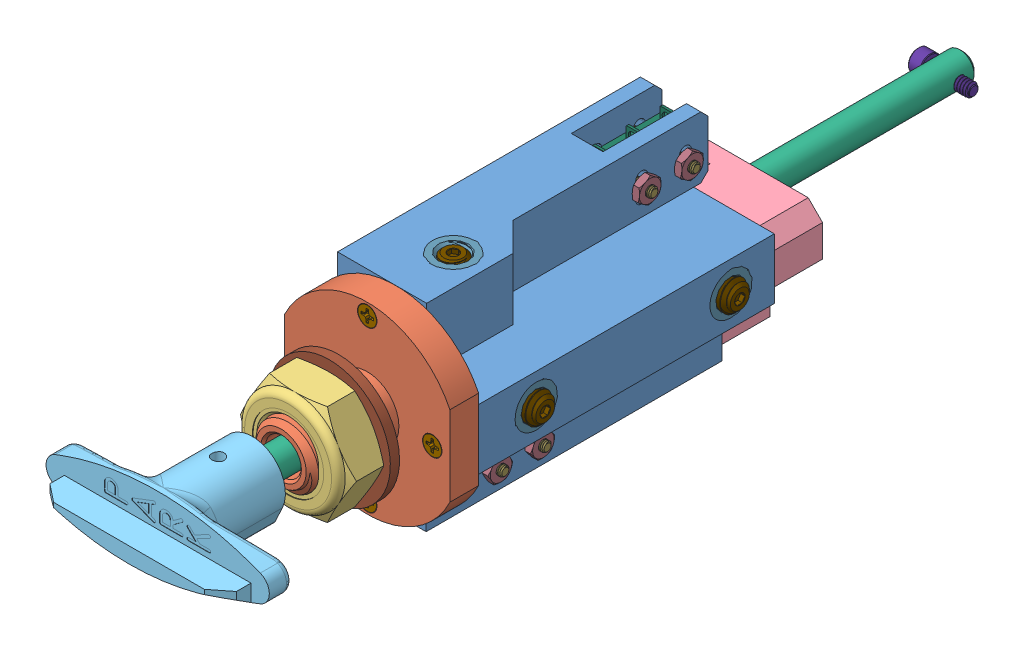
SolidWorks assembly Parking Brake Handle Mechanism, configuration Stowed. Lengths in mm.
Overall size (49.4 44.55 184.53).
50 component instances, 18 part files, 78 mates.
Components (placement in the parent):
- Parking Brake Mechanism Body-1: Parking Brake Mechanism Body [Default] at (0 0 49.2125) x (-1 0 0) z (0 0 -1) size (39.75 43.81 68.58)
- Wing Fold Mechanism Upper Cap-1: Wing Fold Mechanism Upper Cap [Default] at (0 0 -19.177) size (36.58 40.64 28.08)
- Wing Fold Handle Retaining Nut-1: Wing Fold Handle Retaining Nut [Default] at (0 0 -17.145) size (25.66 23.83 11.45)
- Parking Brake Mechanism End Cap-1: Parking Brake Mechanism End Cap [Default] at (0 0 -29.0195) x (-1 0 0) z (0 0 -1) size (39.75 30.18 10.67)
- Parking Brake Handle-1: Parking Brake Handle [Default] at (0 0 6.0325) x (0 1 0) z (0 0 1) size (15.42 49.4 27.31)
- Parking Brake Mechanism Shaft-3: Parking Brake Mechanism Shaft [Default] at (0 0 -46.0375) x (0 -1 0) z (0 0 1) size (6.35 6.35 176.28)
- 6338K411-1: 6338K411 [Default] at (0 0 36.3855) x (1 0 0) z (0 -1 0) size (12.7 6.35 12.7)
- 6338K411-2: 6338K411 [Default] at (0 0 -39.6875) x (-0.923728 -0.383049 0) z (-0.383049 0.923728 0) size (12.7 6.35 12.7)
- 93365A112-14: 93365A112 [Default] at (0 -11.1125 42.7355) x (1 0 0) z (0 -1 0) size (3.58 4.78 3.58)
- 93365A112-15: 93365A112 [Default] at (0 17.68 36.3855) x (1 0 0) z (0 -1 0) size (3.58 4.78 3.58)
- 93365A112-16: 93365A112 [Default] at (14.378 0 36.3855) x (1 0 0) z (0 -1 0) size (3.58 4.78 3.58)
- 93365A112-17: 93365A112 [Default] at (0 -17.68 36.3855) x (1 0 0) z (0 -1 0) size (3.58 4.78 3.58)
- 93365A112-18: 93365A112 [Default] at (-14.378 0 36.3855) x (1 0 0) z (0 -1 0) size (3.58 4.78 3.58)
- 93365A112-12: 93365A112 [Default] at (12.3825 0 -29.0195) x (-0.923728 -0.383049 0) z (0.383049 -0.923728 0) size (3.58 4.78 3.58)
- 93365A112-13: 93365A112 [Default] at (-15.8591 0 -29.0195) x (-0.85131 -0.524663 0) z (0.524663 -0.85131 0) size (3.58 4.78 3.58)
- 93365A112-19: 93365A112 [Default] at (0 -18.2626 -29.0195) x (-0.85131 -0.524663 0) z (0.524663 -0.85131 0) size (3.58 4.78 3.58)
- 96640A027-9: 96640A027 [Default] at (-14.378 0 41.4401) size (4.11 4.11 12.73)
- 96640A027-10: 96640A027 [Default] at (0 -17.68 41.4401) size (4.11 4.11 12.73)
- 96640A027-11: 96640A027 [Default] at (0 17.68 41.4401) size (4.11 4.11 12.73)
- 96640A027-12: 96640A027 [Default] at (14.378 0 41.4401) size (4.11 4.11 12.73)
- 96640A025-1: 96640A025 [Default] at (0 -11.1125 47.7901) size (4.11 4.11 9.56)
- 96640A027-5: 96640A027 [Default] at (12.3825 0 -35.6489) x (0.628171 -0.778076 0) z (0 0 -1) size (4.11 4.11 12.73)
- 96640A027-6: 96640A027 [Default] at (-15.8591 0 -35.6489) x (0.743591 -0.668635 0) z (0 0 -1) size (4.11 4.11 12.73)
- 96640A027-8: 96640A027 [Default] at (0 -6.0071 75.7643) x (-0.410756 0 -0.911745) z (0 -1 0) size (4.11 4.11 12.73)
- 96640A027-13: 96640A027 [Default] at (0 -18.2626 -35.6489) x (0.995409 0.095714 0) z (0 0 -1) size (4.11 4.11 12.73)
- 92141A034-1: 92141A034 [Default] at (0 0 49.0855) x (1 0 0) z (0 -1 0) size (26.97 2.03 26.97)
- 91249A060 - PHS, 2-56 X .625, 18-8, BLACK OXIDE-10: 91249A060 - PHS, 2-56 X .625, 18-8, BLACK OXIDE [91249A060] at (9.1948 -18.2683 21.3928) x (0 0 -1) z (-1 0 0) size (4.24 4.24 17.48)
- 91249A060 - PHS, 2-56 X .625, 18-8, BLACK OXIDE-9: 91249A060 - PHS, 2-56 X .625, 18-8, BLACK OXIDE [91249A060] at (9.1948 -18.2683 12.0329) x (0 0.158553 -0.987351) z (-1 0 0) size (4.24 4.24 17.48)
- 91249A060 - PHS, 2-56 X .625, 18-8, BLACK OXIDE-13: 91249A060 - PHS, 2-56 X .625, 18-8, BLACK OXIDE [91249A060] at (-18.2683 9.1948 21.3928) x (-0.143817 0 0.989604) z (0 -1 0) size (4.24 4.24 17.48)
- 91249A060 - PHS, 2-56 X .625, 18-8, BLACK OXIDE-8: 91249A060 - PHS, 2-56 X .625, 18-8, BLACK OXIDE [91249A060] at (-18.2683 9.1948 12.0329) x (-0.33861 0 0.940927) z (0 -1 0) size (4.24 4.24 17.48)
- 91249A060 - PHS, 2-56 X .625, 18-8, BLACK OXIDE-14: 91249A060 - PHS, 2-56 X .625, 18-8, BLACK OXIDE [91249A060] at (2.9527 12.3755 -27.1886) x (0 0.421154 -0.906989) z (-1 0 0) size (4.24 4.24 17.48)
- 91249A060 - PHS, 2-56 X .625, 18-8, BLACK OXIDE-12: 91249A060 - PHS, 2-56 X .625, 18-8, BLACK OXIDE [91249A060] at (2.9527 12.3748 -17.8127) x (0 0.429957 -0.902849) z (-1 0 0) size (4.24 4.24 17.48)
- 91841A003-5: 91841A003 [Default] at (7.474 -18.2683 21.3928) x (0 -1 0) z (0 0 1) size (4.76 1.72 5.5)
- 91841A003-7: 91841A003 [Default] at (7.474 -18.2683 12.0329) x (0 -0.987351 -0.158553) z (0 -0.158553 0.987351) size (4.76 1.72 5.5)
- 91841A003-9: 91841A003 [Default] at (-18.2683 7.474 21.3928) x (-0.989604 0 -0.143817) z (0.143817 0 -0.989604) size (4.76 1.72 5.5)
- 91841A003-11: 91841A003 [Default] at (-18.2683 7.474 12.0329) x (-0.940927 0 -0.33861) z (0.33861 0 -0.940927) size (4.76 1.72 5.5)
- 91841A003-13: 91841A003 [Default] at (1.2319 12.3755 -27.1886) x (0 -0.906989 -0.421154) z (0 -0.421154 0.906989) size (4.76 1.72 5.5)
- 91841A003-15: 91841A003 [Default] at (1.2319 12.3755 -17.8287) x (0 -0.902849 -0.429957) z (0 -0.429957 0.902849) size (4.76 1.72 5.5)
- 93365A160 - INSERT, .25-20, BRASS, FOR PLASTICS-1: 93365A160 - INSERT, .25-20, BRASS, FOR PLASTICS [93365A160] at (18.288 0 -19.3675) x (0 0.381849 -0.924225) z (0 -0.924225 -0.381849) size (9.53 8.41 9.53)
- 93365A160 - INSERT, .25-20, BRASS, FOR PLASTICS-2: 93365A160 - INSERT, .25-20, BRASS, FOR PLASTICS [93365A160] at (18.288 0 23.6855) x (0 0.523557 -0.85199) z (0 -0.85199 -0.523557) size (9.53 8.41 9.53)
- 93365A160 - INSERT, .25-20, BRASS, FOR PLASTICS-4: 93365A160 - INSERT, .25-20, BRASS, FOR PLASTICS [93365A160] at (0 20.32 23.6855) x (-0.834128 0 -0.551571) z (0.551571 0 -0.834128) size (9.53 8.41 9.53)
- 7658K15-1: 7658K15 [Clipped] at (0 -20.6305 16.6049) x (0 0 1) z (-1 0 0) size (19.99 17.27 6.5)
- 7658K15-2: 7658K15 [Clipped] at (-6.242 14.7377 -22.4007) x (0 0 -1) z (-1 0 0) size (19.99 17.27 6.5)
- 7658K15-3: 7658K15 [Clipped] at (-20.6305 0 16.6049) x (0 0 1) z (0 1 0) size (19.99 17.27 6.5)
- 90176A102 - SPACER, UNTHREADED, .125 X #8 X .250, NYLON 6, BLACK-1: 90176A102 - SPACER, UNTHREADED, .125 X #8 X .250, NYLON 6, BLACK [94639A201] at (-4.7625 0 -25.7175) x (0 0.978585 -0.205844) z (1 0 0) size (6.35 6.35 3.17)
- 91251A108 - SHCS, 4-40 x .375, STEEL, BLACK-OXIDE-1: 91251A108 - SHCS, 4-40 x .375, STEEL, BLACK-OXIDE [91251A108] at (3.175 0 -25.7175) x (0 -0.927315 -0.374281) z (1 0 0) size (4.65 4.65 12.74)
- 91251A108 - SHCS, 4-40 x .375, STEEL, BLACK-OXIDE-2: 91251A108 - SHCS, 4-40 x .375, STEEL, BLACK-OXIDE [91251A108] at (6.35 0 -85.0646) x (0 -0.898283 -0.439417) z (1 0 0) size (4.65 4.65 12.74)
- 5901A142 - SPRING PLUNGER, .25-20 X .625 BODY, .125 X .035 NOSE, 3-7LBS FORCE, STEEL, BLACK-1: 5901A142 - SPRING PLUNGER, .25-20 X .625 BODY, .125 X .035 NOSE, 3-7LBS FORCE, STEEL, BLACK [5901A142] at (0 11.7475 23.6855) x (1 0 0) z (0 0 -1) size (6.42 18.35 6.4)
- 5901A142 - SPRING PLUNGER, .25-20 X .625 BODY, .125 X .035 NOSE, 3-7LBS FORCE, STEEL, BLACK-2: 5901A142 - SPRING PLUNGER, .25-20 X .625 BODY, .125 X .035 NOSE, 3-7LBS FORCE, STEEL, BLACK [5901A142] at (11.7475 0 23.6855) x (0 -1 0) z (0 0 -1) size (6.42 18.35 6.4)
- 5901A142 - SPRING PLUNGER, .25-20 X .625 BODY, .125 X .035 NOSE, 3-7LBS FORCE, STEEL, BLACK-3: 5901A142 - SPRING PLUNGER, .25-20 X .625 BODY, .125 X .035 NOSE, 3-7LBS FORCE, STEEL, BLACK [5901A142] at (11.7475 0 -19.3675) x (0 -1 0) z (0 0 -1) size (6.42 18.35 6.4)
Mates (geometry in assembly coordinates):
- Concentric43: concentric anti-aligned: cylinder of Parking Brake Mechanism Shaft-3 through (0 0 87.1855) axis (0 0 -1) radius 3.175; cylinder of Parking Brake Handle-1 through (0 0 68.1355) axis (0 0 1) radius 3.2385
- Concentric44: concentric aligned: cylinder of Parking Brake Mechanism Shaft-3 through (0 -3.175 75.7643) axis (0 -1 0) radius 0.889; cylinder of Parking Brake Handle-1 through (0 -7.3025 75.7643) axis (0 -1 0) radius 1.3526
- Concentric45: concentric anti-aligned: cylinder of Parking Brake Mechanism Shaft-3 through (-3.175 0 -25.7175) axis (-1 0 0) radius 1.1303; cylinder of 91251A108 - SHCS, 4-40 x .375, STEEL, BLACK-OXIDE-1 through (-9.1948 0 -25.7175) axis (1 0 0) radius 2.3241
- Tangent1: tangent aligned: cylinder of Parking Brake Mechanism Shaft-3 through (0 0 87.1855) axis (0 0 -1) radius 3.175; plane of 91251A108 - SHCS, 4-40 x .375, STEEL, BLACK-OXIDE-1 through (3.175 0 -25.7175) normal (1 0 0)
- Coincident71: coincident anti-aligned: plane of 7658K15-1 through (0 -20.6305 16.6049) normal (-1 0 0); plane of assembly through (0 0 0) normal (1 0 0)
- Distance2: distance = 20.6305 mm aligned: plane of 7658K15-1 through (0 -20.6305 16.6049) normal (0 1 0); plane of assembly through (0 0 0) normal (0 1 0)
- Coincident83: coincident aligned: plane of 7658K15-3 through (-20.6305 0 16.6049) normal (0 1 0); plane of assembly through (0 0 0) normal (0 1 0)
- Coincident84: coincident: plane of 7658K15-1 through (-3.2512 -11.3595 6.61) normal (0 0 -1); plane of 7658K15-3 through (-11.3595 3.2512 6.61) normal (0 0 -1)
- Distance6: distance = 20.6305 mm aligned: plane of 7658K15-3 through (-20.6305 0 16.6049) normal (1 0 0); plane of assembly through (0 0 0) normal (1 0 0)
- Coincident86: coincident aligned: plane of 5901A142 - SPRING PLUNGER, .25-20 X .625 BODY, .125 X .035 NOSE, 3-7LBS FORCE, STEEL, BLACK-1 through (0 11.7475 23.6855) normal (1 0 0); plane of assembly through (0 0 0) normal (1 0 0)
- Tangent3: tangent anti-aligned: cylinder of Parking Brake Mechanism Shaft-3 through (0 0 87.1855) axis (0 0 -1) radius 3.175; plane of 5901A142 - SPRING PLUNGER, .25-20 X .625 BODY, .125 X .035 NOSE, 3-7LBS FORCE, STEEL, BLACK-1 through (0 3.175 23.6855) normal (0 -1 0)
- Concentric47: concentric anti-aligned: cylinder of 91251A108 - SHCS, 4-40 x .375, STEEL, BLACK-OXIDE-1 through (-9.1948 0 -25.7175) axis (1 0 0) radius 2.3241; cylinder of 90176A102 - SPACER, UNTHREADED, .125 X #8 X .250, NYLON 6, BLACK-1 through (-3.175 0 -25.7175) axis (-1 0 0) radius 1.4605
- Coincident87: coincident anti-aligned: plane of 91251A108 - SHCS, 4-40 x .375, STEEL, BLACK-OXIDE-1 through (-6.35 0 -25.7175) normal (1 0 0); plane of 90176A102 - SPACER, UNTHREADED, .125 X #8 X .250, NYLON 6, BLACK-1 through (-6.35 0 -25.7175) normal (-1 0 0)
- Coincident88: coincident aligned: plane of 5901A142 - SPRING PLUNGER, .25-20 X .625 BODY, .125 X .035 NOSE, 3-7LBS FORCE, STEEL, BLACK-1 through (0 11.7475 23.6855) normal (0 0 -1); plane of 5901A142 - SPRING PLUNGER, .25-20 X .625 BODY, .125 X .035 NOSE, 3-7LBS FORCE, STEEL, BLACK-2 through (11.7475 0 23.6855) normal (0 0 -1)
- Coincident89: coincident anti-aligned: plane of 5901A142 - SPRING PLUNGER, .25-20 X .625 BODY, .125 X .035 NOSE, 3-7LBS FORCE, STEEL, BLACK-2 through (11.7475 0 23.6855) normal (0 -1 0); plane of assembly through (0 0 0) normal (0 1 0)
- Tangent4: tangent anti-aligned: cylinder of Parking Brake Mechanism Shaft-3 through (0 0 87.1855) axis (0 0 -1) radius 3.175; plane of 5901A142 - SPRING PLUNGER, .25-20 X .625 BODY, .125 X .035 NOSE, 3-7LBS FORCE, STEEL, BLACK-2 through (3.175 0 23.6855) normal (-1 0 0)
- Coincident91: coincident: plane of Parking Brake Mechanism Body-1 through (-9.4615 3.302 49.2125) normal (0 -1 0); line of 7658K15-2 through (-7.3469 3.302 -20.3306) axis (1 0 0)
- Coincident92: coincident aligned: plane of 5901A142 - SPRING PLUNGER, .25-20 X .625 BODY, .125 X .035 NOSE, 3-7LBS FORCE, STEEL, BLACK-2 through (11.7475 0 23.6855) normal (-1 0 0); plane of 5901A142 - SPRING PLUNGER, .25-20 X .625 BODY, .125 X .035 NOSE, 3-7LBS FORCE, STEEL, BLACK-3 through (11.7475 0 -19.3675) normal (-1 0 0)
- Coincident93: coincident aligned: plane of 5901A142 - SPRING PLUNGER, .25-20 X .625 BODY, .125 X .035 NOSE, 3-7LBS FORCE, STEEL, BLACK-2 through (11.7475 0 23.6855) normal (0 -1 0); plane of 5901A142 - SPRING PLUNGER, .25-20 X .625 BODY, .125 X .035 NOSE, 3-7LBS FORCE, STEEL, BLACK-3 through (11.7475 0 -19.3675) normal (0 -1 0)
- Concentric49: concentric: cylinder of assembly; cylinder of Parking Brake Mechanism Body-1 through (0 0 -39.6875) axis (0 0 -1) radius 4.7879; cylinder of 6338K411-2 through (0 0 -33.3375) axis (0 0 -1) radius 4.7625
- Coincident95: coincident: plane of assembly; plane of Parking Brake Mechanism Body-1 through (0 0 -39.6875) normal (0 0 -1); plane of 6338K411-2 through (0 0 -39.6875) normal (0 0 -1)
- Concentric50: concentric anti-aligned: cylinder of Parking Brake Mechanism Shaft-3 through (-3.175 0 -85.0646) axis (-1 0 0) radius 1.1303; cylinder of 91251A108 - SHCS, 4-40 x .375, STEEL, BLACK-OXIDE-2 through (-6.0198 0 -85.0646) axis (1 0 0) radius 2.3241
- Tangent5: tangent anti-aligned: cylinder of Parking Brake Mechanism Shaft-3 through (0 0 87.1855) axis (0 0 -1) radius 3.175; plane of 91251A108 - SHCS, 4-40 x .375, STEEL, BLACK-OXIDE-2 through (-3.175 0 -85.0646) normal (1 0 0)
- Concentric51: concentric anti-aligned: cone of Parking Brake Mechanism Body-1 through (12.3825 0 -29.0195) axis (0 0 1); cylinder of 93365A112-12 through (12.3825 0 -29.0195) axis (0 0 -1) radius 1.6116
- Coincident96: coincident aligned: plane of Parking Brake Mechanism Body-1 through (0 0 -29.0195) normal (0 0 -1); plane of 93365A112-12 through (14.0366 0.6859 -29.0195) normal (0 0 -1)
- Concentric52: concentric anti-aligned: cone of Parking Brake Mechanism Body-1 through (-15.8591 0 -29.0195) axis (0 0 1); cylinder of 93365A112-13 through (-15.8591 0 -29.0195) axis (0 0 -1) radius 1.6116
- Coincident97: coincident aligned: plane of Parking Brake Mechanism Body-1 through (0 0 -29.0195) normal (0 0 -1); plane of 93365A112-13 through (-14.3347 0.9395 -29.0195) normal (0 0 -1)
- Concentric57: concentric aligned: cylinder of 91249A060 - PHS, 2-56 X .625, 18-8, BLACK OXIDE-10 through (8.6868 -18.2683 21.3928) axis (1 0 0) radius 2.1209; cylinder of 7658K15-1 through (-3.2512 -18.2683 21.3928) axis (1 0 0) radius 1.1049
- Concentric59: concentric aligned: cylinder of 91249A060 - PHS, 2-56 X .625, 18-8, BLACK OXIDE-10 through (8.6868 -18.2683 21.3928) axis (1 0 0) radius 2.1209; circle of 91841A003-5
- Coincident102: coincident anti-aligned: plane of 91841A003-5 through (7.1882 -15.8871 20.018) normal (-1 0 0); plane of Parking Brake Mechanism Body-1 through (7.1882 92.3005 55.5625) normal (1 0 0)
- Concentric60: concentric: cylinder of ? through (8.6868 -18.2683 12.0329) axis (1 0 0) radius 2.1209; unknown of ?
- Concentric61: concentric aligned: cylinder of 7658K15-1 through (-3.2512 -18.2683 12.0329) axis (1 0 0) radius 1.1049; cylinder of ? through (8.6868 -18.2683 12.0329) axis (1 0 0) radius 2.1209
- Coincident104: coincident anti-aligned: plane of Parking Brake Mechanism Body-1 through (7.1882 92.3005 55.5625) normal (1 0 0); plane of 91841A003-7 through (7.1882 -15.6992 11.053) normal (-1 0 0)
- Concentric63: concentric: cylinder of ? through (-18.2683 8.6868 21.3928) axis (0 1 0) radius 2.1209; unknown of ?
- Concentric64: concentric anti-aligned: cylinder of 7658K15-3 through (-18.2683 3.2512 21.3928) axis (0 -1 0) radius 1.1049; cylinder of ? through (-18.2683 8.6868 21.3928) axis (0 1 0) radius 2.1209
- Concentric66: concentric: cylinder of ? through (-18.2683 8.6868 12.0329) axis (0 1 0) radius 2.1209; unknown of ?
- Concentric67: concentric anti-aligned: cylinder of 7658K15-3 through (-18.2683 3.2512 12.0329) axis (0 -1 0) radius 1.1049; cylinder of ? through (-18.2683 8.6868 12.0329) axis (0 1 0) radius 2.1209
- Concentric70: concentric aligned: cylinder of 7658K15-2 through (-9.4932 12.3755 -27.1886) axis (1 0 0) radius 1.1049; cylinder of ? through (8.6868 -18.2683 21.3928) axis (1 0 0) radius 2.1209
- Coincident110: coincident anti-aligned: plane of Parking Brake Mechanism Body-1 through (0.4381 -93.4029 -39.6875) normal (1 0 0); plane of 91841A003-13 through (0.4381 15.1143 -27.4327) normal (-1 0 0)
- Coincident112: coincident anti-aligned: plane of Parking Brake Mechanism Body-1 through (0.4381 -93.4029 -39.6875) normal (1 0 0); plane of 91841A003-15 through (0.4381 15.1165 -18.0461) normal (-1 0 0)
- Concentric75: concentric anti-aligned: cone of Parking Brake Mechanism Body-1 through (18.288 0 -19.3675) axis (-1 0 0); cylinder of 93365A160 - INSERT, .25-20, BRASS, FOR PLASTICS-1 through (18.288 0 -19.3675) axis (1 0 0) radius 4.4323
- Coincident113: coincident aligned: plane of Parking Brake Mechanism Body-1 through (18.288 8.8573 -39.6875) normal (1 0 0); plane of 93365A160 - INSERT, .25-20, BRASS, FOR PLASTICS-1 through (18.288 0 -19.3675) normal (1 0 0)
- Concentric76: concentric anti-aligned: cone of Parking Brake Mechanism Body-1 through (18.288 0 23.6855) axis (-1 0 0); cylinder of 93365A160 - INSERT, .25-20, BRASS, FOR PLASTICS-2 through (18.288 0 23.6855) axis (1 0 0) radius 4.4323
- Coincident114: coincident aligned: plane of Parking Brake Mechanism Body-1 through (18.288 8.8573 -39.6875) normal (1 0 0); plane of 93365A160 - INSERT, .25-20, BRASS, FOR PLASTICS-2 through (18.288 0 23.6855) normal (1 0 0)
- Concentric77: concentric anti-aligned: cone of Parking Brake Mechanism Body-1 through (0 20.32 23.6855) axis (0 -1 0); cylinder of 93365A160 - INSERT, .25-20, BRASS, FOR PLASTICS-4 through (0 20.32 23.6855) axis (0 1 0) radius 4.4323
- Coincident115: coincident aligned: plane of Parking Brake Mechanism Body-1 through (0 20.32 -39.6875) normal (0 1 0); plane of 93365A160 - INSERT, .25-20, BRASS, FOR PLASTICS-4 through (0 20.32 23.6855) normal (0 1 0)
- Concentric78: concentric aligned: cone of Parking Brake Handle-1 through (0 -7.3025 75.7643) axis (0 1 0); cone of 96640A027-8 through (0 -7.3025 75.7643) axis (0 1 0)
- Tangent6: tangent aligned: cylinder of Parking Brake Handle-1 through (0 54.0707 89.0905) axis (0 0 -1) radius 61.3732; plane of 96640A027-8 through (0 -7.3025 75.7643) normal (0 -1 0)
- Concentric80: concentric aligned: cylinder of Parking Brake Mechanism Shaft-3 through (0 0 87.1855) axis (0 0 -1) radius 3.175; cylinder of Parking Brake Mechanism Body-1 through (0 0 49.2125) axis (0 0 -1) radius 4.7625
- Concentric81: concentric aligned: cylinder of Parking Brake Mechanism Shaft-3 through (0 0 87.1855) axis (0 0 -1) radius 3.175; cylinder of Parking Brake Mechanism Body-1 through (0 0 49.2125) axis (0 0 -1) radius 4.7625
- Parallel15: parallel: plane of Parking Brake Mechanism Body-1 through (0 -23.495 -39.6875) normal (0 -1 0); plane of Parking Brake Handle-1 through (0 0 92.2655) normal (0 1 0)
- Parallel16: parallel: plane of Wing Fold Mechanism Upper Cap-1 through (-18.288 8.8573 36.3855) normal (-1 0 0); plane of Parking Brake Handle-1 through (0 0 92.2655) normal (0 1 0)
- Concentric82: concentric anti-aligned: cylinder of Parking Brake Mechanism Shaft-3 through (0 0 87.1855) axis (0 0 -1) radius 3.175; cylinder of Wing Fold Mechanism Upper Cap-1 through (0 0 42.7355) axis (0 0 1) radius 3.9688
- LimitAngle3: limit planar angle = 1.570796 rad anti-aligned: plane of Wing Fold Mechanism Upper Cap-1 through (18.288 -8.8573 36.3855) normal (1 0 0); plane of Parking Brake Handle-1 through (0 0 92.2655) normal (0 1 0)
- Perpendicular3: perpendicular: plane of Wing Fold Mechanism Upper Cap-1 through (-18.288 8.8573 36.3855) normal (-1 0 0); plane of Parking Brake Handle-1 through (0 0 92.2655) normal (0 1 0)
- Coincident119: coincident: plane of Wing Fold Mechanism Upper Cap-1 through (0 0 36.3855) normal (0 0 -1); plane of Parking Brake Mechanism Body-1 through (0 0 36.3855) normal (0 0 1)
- Parallel17: parallel: plane of Wing Fold Mechanism Upper Cap-1 through (18.288 -8.8573 36.3855) normal (1 0 0); plane of Parking Brake Mechanism Body-1 through (18.288 8.8573 -39.6875) normal (1 0 0)
- LimitDistance3: limit distance = 19.05 mm aligned: plane of Parking Brake Handle-1 through (0 0 68.1355) normal (0 0 -1); plane of 92141A034-1 through (0 0 49.0855) normal (0 0 -1)
- Distance15: distance = 19.05 mm: plane of Parking Brake Handle-1 through (0 0 68.1355) normal (0 0 -1); plane of 92141A034-1 through (0 0 49.0855) normal (0 0 -1)
- Distance16: distance = 87.63 mm: plane of 5901A142 - SPRING PLUNGER, .25-20 X .625 BODY, .125 X .035 NOSE, 3-7LBS FORCE, STEEL, BLACK-3 through (11.7475 0 -19.3675) normal (0 0 -1); plane of 92141A034-1 through (0 0 49.0855) normal (0 0 -1)
- InPlace1: in place: plane of Parking Brake Mechanism Body-1 through (0 0 -29.0195) normal (0 0 -1); plane of Parking Brake Mechanism End Cap-1 through (0 0 -29.0195) normal (0 0 -1); moOrthogonalPlaneRef_w of Parking Brake Mechanism Body-1 through (0 0 -29.0195) normal (0 0 -1); plane of Parking Brake Mechanism End Cap-1 through (0 0 -29.0195) normal (0 1 0); plane of Parking Brake Mechanism Body-1 through (0 0 -29.0195) normal (0 0 -1); plane of Parking Brake Mechanism End Cap-1 through (0 0 -29.0195) normal (-1 0 0); plane of Parking Brake Mechanism Body-1 through (0 0 -29.0195) normal (0 0 -1); unknown of Parking Brake Mechanism End Cap-1
- Coincident120: coincident aligned: plane of Parking Brake Mechanism Body-1; plane of Parking Brake Mechanism End Cap-1
- Coincident121: coincident aligned: moOrthogonalPlaneRef_w of Parking Brake Mechanism Body-1 through (0 0 -29.0195) normal (0 1 0); plane of Parking Brake Mechanism End Cap-1 through (0 0 -29.0195) normal (0 1 0)
- Coincident122: coincident anti-aligned: moOrthogonalPlaneRef_w of Parking Brake Mechanism Body-1 through (0 0 -29.0195) normal (1 0 0); plane of Parking Brake Mechanism End Cap-1 through (0 0 -29.0195) normal (-1 0 0)
- Concentric83: concentric aligned: cone of Parking Brake Mechanism Body-1 through (0 -18.2626 -29.0195) axis (0 0 1); cone of 93365A112-19 through (0 -18.2626 -27.3959) axis (0 0 1)
- Coincident120: coincident aligned: plane of Parking Brake Mechanism Body-1 through (0 0 -29.0195) normal (0 0 -1); plane of 93365A112-19 through (1.5244 -17.3231 -29.0195) normal (0 0 -1)
- Concentric84: concentric aligned: cone of Parking Brake Mechanism End Cap-1 through (0 -18.2626 -36.9443) axis (0 0 1); cone of 96640A027-13 through (0 -18.2626 -36.9443) axis (0 0 1)
- Coincident121: coincident aligned: plane of 96640A027-5 through (12.3825 0 -36.9443) normal (0 0 -1); plane of 96640A027-13 through (0 -18.2626 -36.9443) normal (0 0 -1)
- Coincident122: coincident anti-aligned: plane of Parking Brake Mechanism Body-1 through (-12.9223 -93.4029 55.5625) normal (-1 0 0); plane of 91249A060 - PHS, 2-56 X .625, 18-8, BLACK OXIDE-12 through (-12.9223 12.3748 -17.8127) normal (1 0 0)
- Coincident123: coincident anti-aligned: plane of Parking Brake Mechanism Body-1 through (-12.9223 -93.4029 55.5625) normal (-1 0 0); plane of 91249A060 - PHS, 2-56 X .625, 18-8, BLACK OXIDE-14 through (-12.9223 12.3755 -27.1886) normal (1 0 0)
- Coincident124: coincident anti-aligned: plane of Parking Brake Mechanism Body-1 through (-3.683 -6.6802 6.356) normal (0 -1 0); plane of 91249A060 - PHS, 2-56 X .625, 18-8, BLACK OXIDE-8 through (-18.2683 -6.6802 12.0329) normal (0 1 0)
- Coincident125: coincident anti-aligned: plane of Parking Brake Mechanism Body-1 through (-3.683 -6.6802 6.356) normal (0 -1 0); plane of 91249A060 - PHS, 2-56 X .625, 18-8, BLACK OXIDE-13 through (-18.2683 -6.6802 21.3928) normal (0 1 0)
- Coincident126: coincident anti-aligned: plane of Parking Brake Mechanism Body-1 through (-3.683 6.6802 26.8538) normal (0 1 0); plane of 91841A003-11 through (-16.4933 6.6802 14.1328) normal (0 -1 0)
- Coincident127: coincident anti-aligned: plane of Parking Brake Mechanism Body-1 through (-3.683 6.6802 26.8538) normal (0 1 0); plane of 91841A003-9 through (-16.1095 6.6802 23.0958) normal (0 -1 0)
- Coincident128: coincident anti-aligned: plane of Parking Brake Mechanism Body-1 through (-6.6802 92.8851 -39.6875) normal (-1 0 0); plane of 91249A060 - PHS, 2-56 X .625, 18-8, BLACK OXIDE-9 through (-6.6802 -18.2683 12.0329) normal (1 0 0)
- Coincident129: coincident anti-aligned: plane of Parking Brake Mechanism Body-1 through (-6.6802 92.8851 -39.6875) normal (-1 0 0); plane of 91249A060 - PHS, 2-56 X .625, 18-8, BLACK OXIDE-10 through (-6.6802 -18.2683 21.3928) normal (1 0 0)
- Coincident130: coincident anti-aligned: plane of Parking Brake Mechanism Body-1 through (6.6802 92.8851 55.5625) normal (1 0 0); plane of 91841A003-5 through (6.6802 -15.8871 20.018) normal (-1 0 0)
- Coincident131: coincident anti-aligned: plane of Parking Brake Mechanism Body-1 through (6.6802 92.8851 55.5625) normal (1 0 0); plane of 91841A003-7 through (6.6802 -15.6992 11.053) normal (-1 0 0)
